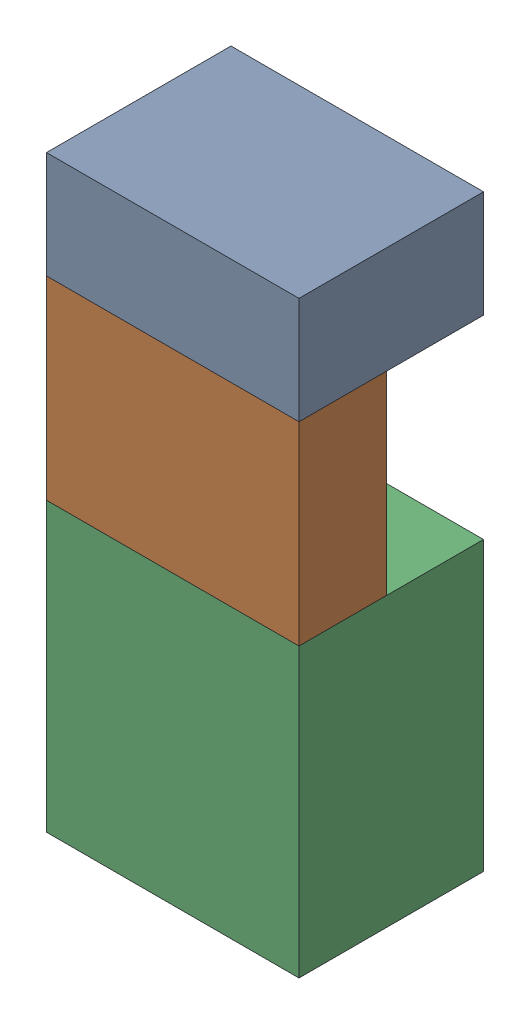
SolidWorks assembly SUP_K5, configuration Default. Lengths in mm.
Overall size (13 30.3 9.5).
6 component instances, 3 part files, 0 mates.
Components (placement in the parent):
- 1151724928-1: 1151724928 [Default] at (67.945 41.975 0) size (13 5.5 9.5)
  - Extruded_2-1: Extruded_2 [Default] at origin size (13 5.5 9.5)
- 1151725064-1: 1151725064 [Default] at (67.945 34.225 5) size (13 10 4.5)
  - Extruded_3-1: Extruded_3 [Default] at origin size (13 10 4.5)
- 1151724792-1: 1151724792 [Default] at (67.945 21.825 0) size (13 14.8 9.5)
  - Extruded_4-1: Extruded_4 [Default] at origin size (13 14.8 9.5)
